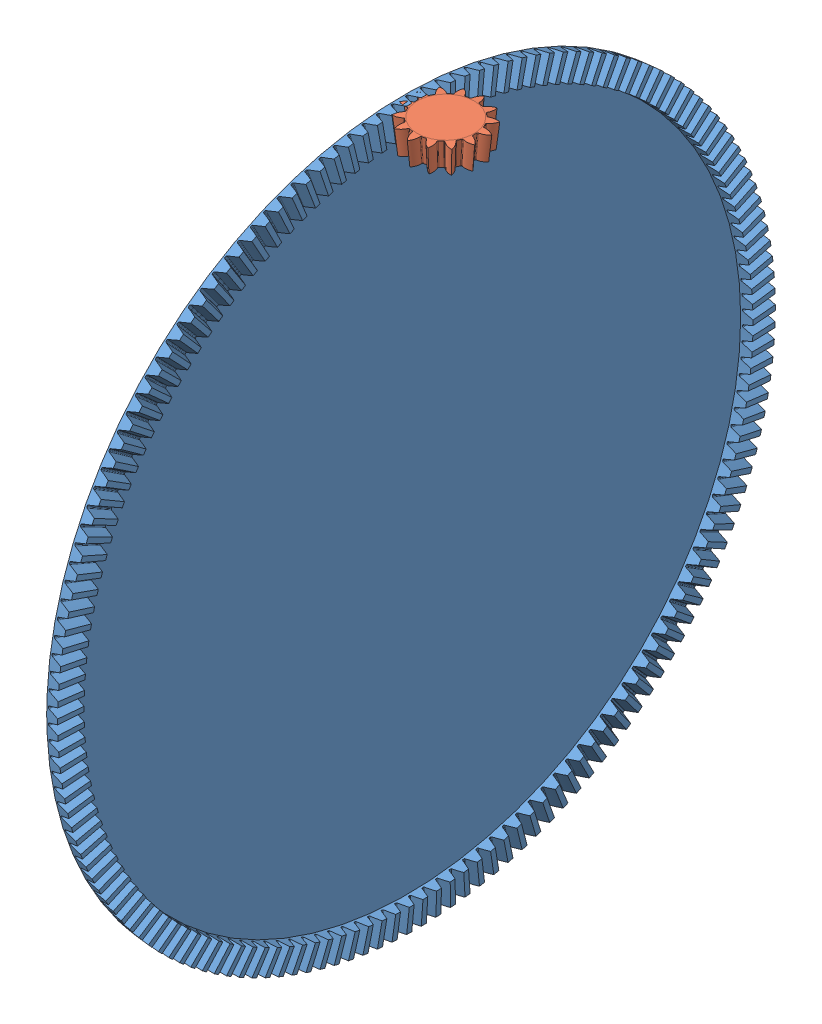
SolidWorks assembly Gear Subassembly v2, configuration Default. Lengths in mm.
Overall size (44.11 401.27 401.26).
2 component instances, 2 part files, 3 mates.
Components (placement in the parent):
- big_gear-1: big_gear [Inch - Straight bevel gear 3.5DP 154GT 14PT 20PA 1.5FW ---154O3.0H2.0MD6.0N] at origin size (7.95 401.23 401.26)
- small_gear-1: small_gear [Inch - Straight bevel pinion 3.5DP14PT 154GT 20PA 1.5FW ---14O3.0H2.0MD0.5N] at (23.1011 200.6532 0) x (0 -1 0) z (0 0 1) size (15.93 42.01 43.08)
Mates (geometry in assembly coordinates):
- Parallel1: parallel anti-aligned: plane of small_gear-1 through (23.1011 200.6532 0) normal (0 -1 0)
- Coincident3: coordinate: point of big_gear-1
- Coincident5: coincident aligned: plane of small_gear-1 through (23.1011 200.6532 0) normal (0 0 1)
